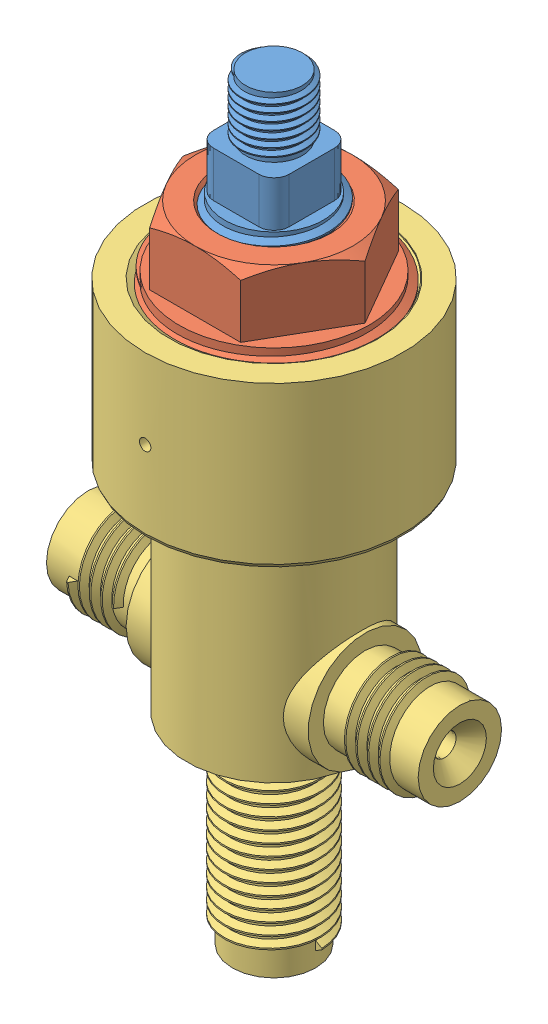
SolidWorks assembly Сборка5, configuration По умолчанию. Lengths in mm.
Overall size (49 100.07 34).
6 component instances, 6 part files, 12 mates.
Components (placement in the parent):
- Вставная штука 2-1: Вставная штука 2 [По умолчанию] at (14.8579 -10.1459 32.7028) size (20 32.7 20)
- Гайка-1: Гайка [По умолчанию] at (14.8579 -20.6459 32.7028) x (1 0 0) z (0 1 0) size (26.9 26.9 24.02)
- Большая штука-1: Большая штука [По умолчанию] at (14.8579 -5.5147 32.7028) x (-1 0 0) z (0 0 1) size (49 76.92 34)
- Маленькая шайба-1: Маленькая шайба [По умолчанию] at (14.8579 -18.0147 32.7028) x (0.837169 0 -0.546944) z (0.546944 0 0.837169) size (18 10 18)
- Пружина-1: Пружина [По умолчанию] at (14.8579 -41.5147 32.7028) x (0.837169 0 -0.546944) z (0.546944 0 0.837169) size (18.03 21.49 18.03)
- Болт-1: Болт [По умолчанию] at (14.8579 -20.0147 32.7028) x (-1 0 0) z (0 0 1) size (18 23.5 18)
Mates (geometry in assembly coordinates):
- Параллельность1: parallel anti-aligned: plane of Вставная штука 2-1 through (22.1698 -4.0834 32.7028) normal (0 0 1); plane of Гайка-1 through (22.1698 -4.0834 32.7028) normal (0 0 -1)
- Концентричный3: concentric aligned: circle of Вставная штука 2-1; circle of Гайка-1
- Совпадение7: coincident anti-aligned: plane of Вставная штука 2-1 through (14.8579 -4.6459 32.7028) normal (0 1 0); plane of Гайка-1 through (14.8579 -4.6459 32.7028) normal (0 -1 0)
- Совпадение8: coincident anti-aligned: plane of Большая штука-1 through (14.8579 -41.5147 32.7028) normal (0 1 0); plane of Пружина-1 through (14.8579 -41.5147 32.7028) normal (0 -1 0)
- Концентричный4: concentric: cylinder of Большая штука-1 through (14.8579 -5.5147 32.7028) axis (0 -1 0) radius 1.5; point of Пружина-1
- Концентричный5: concentric aligned: cylinder of Большая штука-1 through (14.8579 -41.5147 32.7028) axis (0 1 0) radius 9; cylinder of Болт-1 through (14.8579 -20.0147 32.7028) axis (0 1 0) radius 4.5
- Совпадение14: coincident anti-aligned: plane of Пружина-1 through (14.8579 -21.5147 32.7028) normal (0 1 0); plane of Болт-1 through (19.3579 -21.5147 32.7028) normal (0 -1 0)
- Совпадение15: coincident anti-aligned: plane of Маленькая шайба-1 through (11.5092 -18.0147 34.8906) normal (0 -1 0); plane of Болт-1 through (23.8579 -18.0147 32.7028) normal (0 1 0)
- Концентричный6: concentric anti-aligned: cylinder of Большая штука-1 through (14.8579 -21.5147 32.7028) axis (0 1 0) radius 13; cylinder of Маленькая шайба-1 through (14.8579 -29.7023 32.7028) axis (0 -1 0) radius 7
- Концентричный7: concentric anti-aligned: cylinder of Гайка-1 through (14.8579 -4.6459 32.7028) axis (0 1 0) radius 12.5; cylinder of Большая штука-1 through (14.8579 -81.5147 32.7028) axis (0 -1 0) radius 17
- Параллельность2: parallel anti-aligned: plane of Гайка-1 through (28.3051 -13.6069 32.7028) normal (0 0 1); plane of Большая штука-1 through (28.6698 -17.9522 32.7028) normal (0 0 -1)
- Совпадение19: coincident aligned: cone of Гайка-1 through (14.8579 -20.6459 32.7028) axis (0 1 0); circle of Большая штука-1
